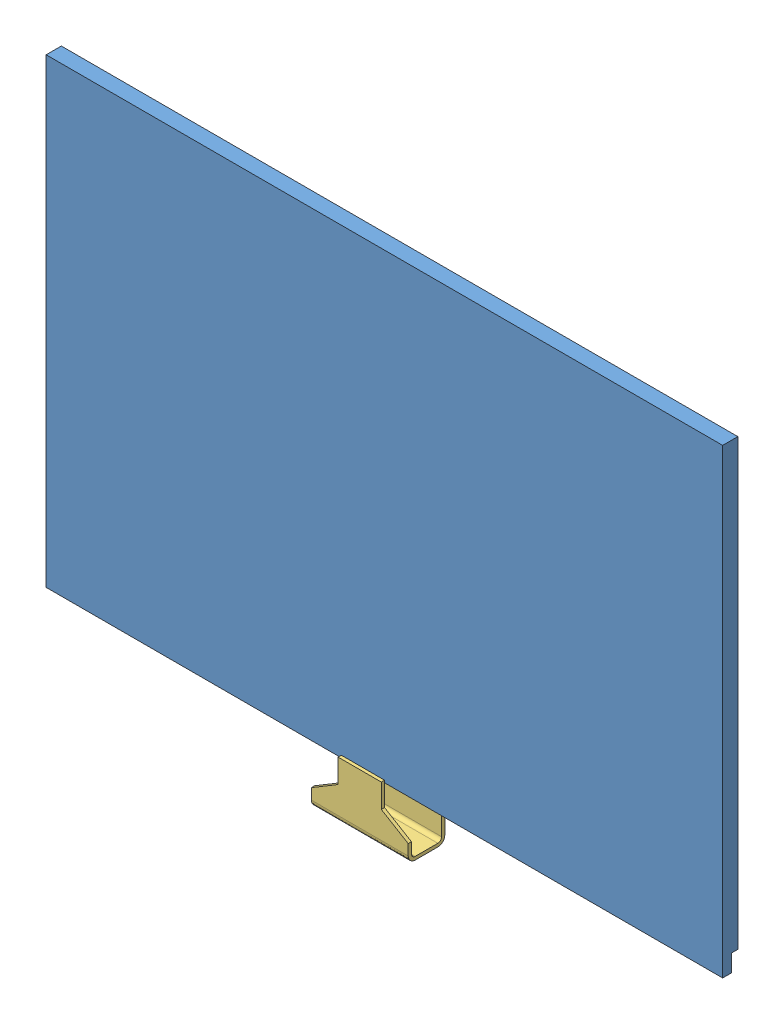
SolidWorks assembly LS027B7DH01 LCD, configuration Défaut. Lengths in mm.
Overall size (62.8 45.97 3.94).
4 component instances, 3 part files, 0 mates.
Components (placement in the parent):
- LS027B7DH01 LCD.stp-1: LS027B7DH01 LCD.stp [Défaut] at origin size (62.8 45.97 3.94)
  - eBom-prt0.stp-1: eBom-prt0.stp [Défaut] at origin size (62.8 42.82 1.64)
  - eBom-prt1.stp-1: eBom-prt1.stp [Défaut] at (2 5.54 -0.835) size (58.8 35.28 0.01)
  - eBom-prt2.stp-1: eBom-prt2.stp [Défaut] at (31.4 -0.8 -0.15) x (0 -1 0) z (1 0 0) size (5.35 3.4 9)
